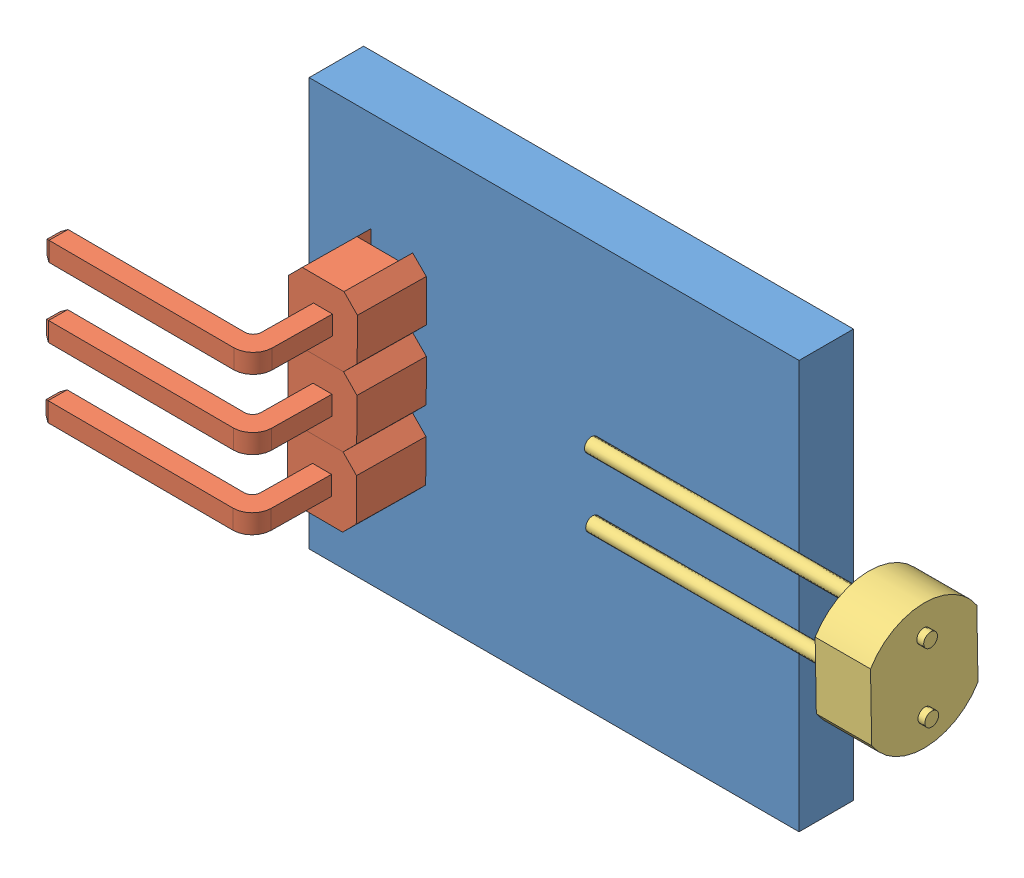
SolidWorks assembly KY-018_v2, configuration Default. Lengths in mm.
Overall size (27.44 15 8.55).
4 component instances, 3 part files, 0 mates.
Components (placement in the parent):
- KY-018.stp-1: KY-018.stp [Default] at origin size (27.44 15 8.55)
  - board.stp-1: board.stp [Default] at (-16.037 -3.7963 -1) size (18 15 2)
  - User Library-PLS-3R.stp-1: User Library-PLS-3R.stp [Default] at (-13.0023 6.2551 0.9782) x (-0.999988 -0.001112 -0.004738) z (-0.001075 0.99997 -0.007711) size (8.62 8.45 7.62)
  - User Library-Photoresistor.stp-1: User Library-Photoresistor.stp [Default] at (6.8069 3.7234 1.2444) x (-0.001332 0.017452 -0.999847) z (0.000098 -0.999848 -0.017452) size (3.91 12.45 4.62)
